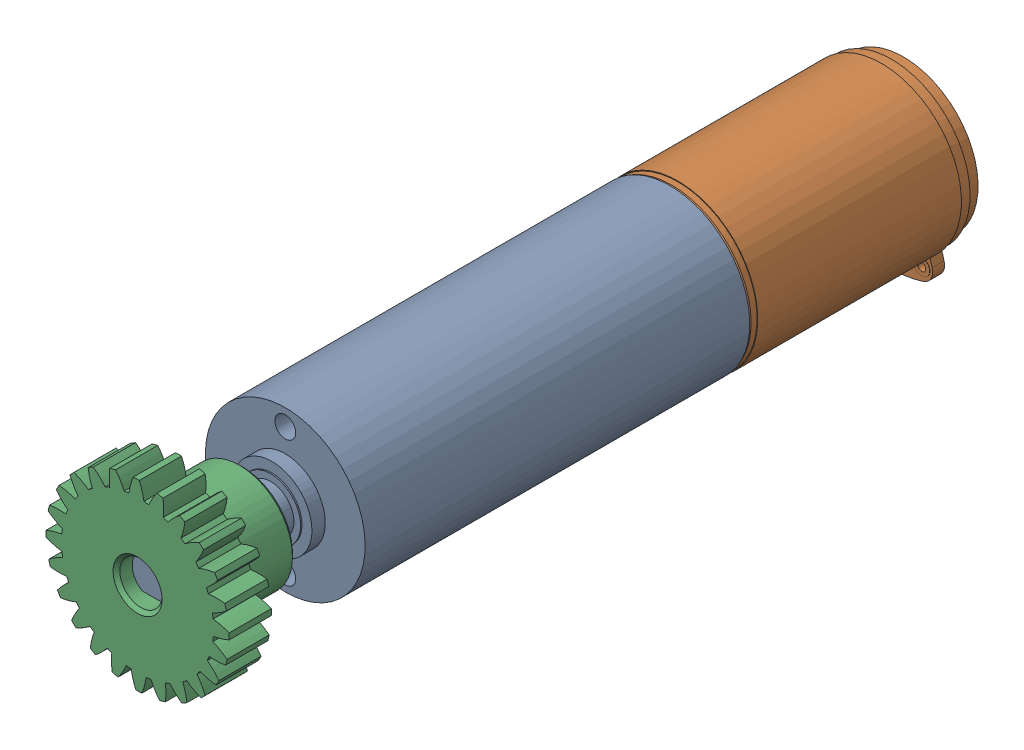
SolidWorks assembly A-800139-50-121319-Motor-And-Gear-Box, configuration Default. Lengths in mm.
Overall size (13.95 14.73 58.1).
3 component instances, 3 part files, 4 mates.
Components (placement in the parent):
- 12_4K 4stages.stp-1: 12_4K 4stages.stp [Default] at (14.8975 19.5643 39.61) size (12 12 38.9)
- DM1220S(2R)_31.stp-1: DM1220S(2R)_31.stp [Default] at (14.8975 19.5643 10.71) size (12 13.75 24.1)
- ONDRIVES_US_CORP_SG48P10A-24-1: ONDRIVES_US_CORP_SG48P10A-24 [Default] at (14.8975 19.5643 50.7098) x (0 0 -1) z (0.014094 -0.999901 0) size (7.92 13.76 13.76)
Mates (geometry in assembly coordinates):
- Coincident1: coincident: plane of 12_4K 4stages.stp-1 through (14.8975 16.5643 10.71) normal (0 0 -1); plane of DM1220S(2R)_31.stp-1 through (14.8975 19.5643 10.71) normal (0 0 1)
- Concentric1: concentric anti-aligned: cylinder of 12_4K 4stages.stp-1 through (14.8975 19.5643 25.16) axis (0 0 1) radius 6; cylinder of DM1220S(2R)_31.stp-1 through (14.8975 19.5643 10.71) axis (0 0 -1) radius 6
- Concentric2: concentric: cylinder of 12_4K 4stages.stp-1 through (14.8975 19.5643 45.61) axis (0 0 1) radius 1.5; cylinder of ONDRIVES_US_CORP_SG48P10A-24-1 through (14.8975 19.5643 56.4891) axis (0 0 -1) radius 1.585
- Distance1: distance = 3.175 mm anti-aligned: plane of ONDRIVES_US_CORP_SG48P10A-24-1 through (16.4823 19.5866 42.785) normal (0 0 -1); plane of 12_4K 4stages.stp-1 through (14.8975 15.0643 39.61) normal (0 0 1)
